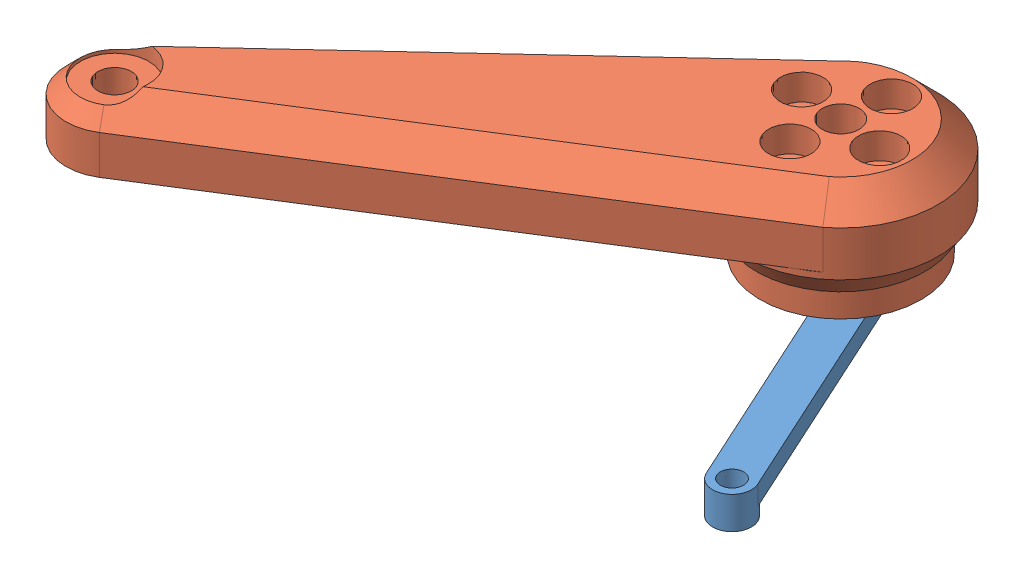
SolidWorks assembly up-leg, configuration Default. Lengths in mm.
Overall size (104.22 23 86.25).
2 component instances, 2 part files, 2 mates.
Components (placement in the parent):
- connecting rod-1: connecting rod [Default] at (-24.0169 10.881 18.7986) x (0 -1 0) z (-0.416378 0 -0.909191) size (5 6 56)
- upper_leg-1: upper_leg [Default] at (-58.6243 18.881 -32.0831) x (0.792896 0 -0.609357) z (0 1 0) size (102.5 30 18)
Mates (geometry in assembly coordinates):
- Concentric4: concentric aligned: circle of connecting rod-1; circle of upper_leg-1
- Coincident5: coincident anti-aligned: plane of connecting rod-1 through (-57.7158 10.881 -39.0239) normal (0 1 0); plane of upper_leg-1 through (-58.6243 10.881 -32.0831) normal (0 -1 0)
